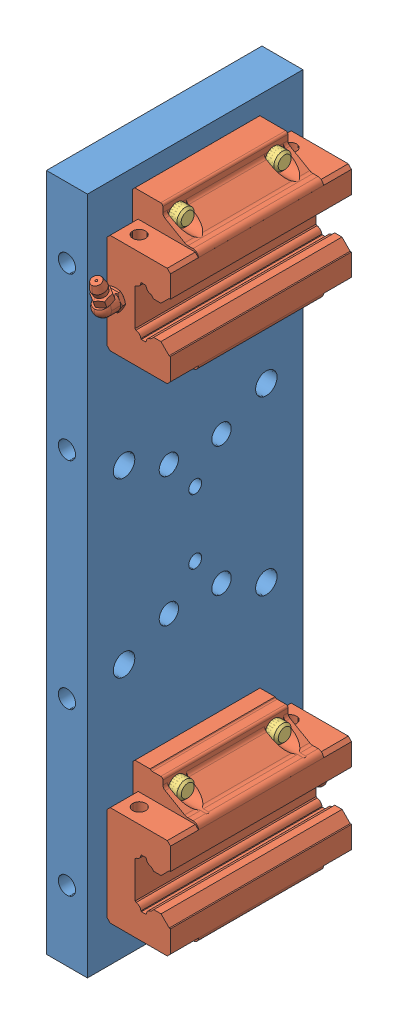
SolidWorks assembly Montagem_plataforma_patins, configuration Valor predeterminado. Lengths in mm.
Overall size (49.52 315 108.05).
11 component instances, 3 part files, 22 mates.
Components (placement in the parent):
- Plataforma-1: Plataforma [Valor predeterminado] at (-159.0513 138.7252 137.5684) x (0 1 0) z (0 0 1) size (315 19.02 100)
- KRH25-FL-N-Z0-1: KRH25-FL-N-Z0 [Valor predeterminado] at (-128.5513 253.7252 179.5684) x (0 0 -1) z (-1 0 0) size (96 70 30.5)
- KRH25-FL-N-Z0-2: KRH25-FL-N-Z0 [Valor predeterminado] at (-128.5513 23.7252 95.5184) x (0 0 1) z (-1 0 0) size (96 70 30.5)
- Allen_M8x30-1: Allen_M8x30 [ISO 4762 M8 x 30] at (-178.0713 -4.7748 160.0184) size (38 13 13)
- Allen_M8x30-2: Allen_M8x30 [ISO 4762 M8 x 30] at (-178.0713 52.2252 160.0184) size (38 13 13)
- Allen_M8x30-3: Allen_M8x30 [ISO 4762 M8 x 30] at (-178.0713 52.2252 115.0184) size (38 13 13)
- Allen_M8x30-4: Allen_M8x30 [ISO 4762 M8 x 30] at (-178.0713 -4.7748 115.0184) size (38 13 13)
- Allen_M8x30-5: Allen_M8x30 [ISO 4762 M8 x 30] at (-178.0713 225.2252 160.0684) size (38 13 13)
- Allen_M8x30-6: Allen_M8x30 [ISO 4762 M8 x 30] at (-178.0713 225.2252 115.0684) size (38 13 13)
- Allen_M8x30-7: Allen_M8x30 [ISO 4762 M8 x 30] at (-178.0713 282.2252 115.0684) size (38 13 13)
- Allen_M8x30-8: Allen_M8x30 [ISO 4762 M8 x 30] at (-178.0713 282.2252 160.0684) size (38 13 13)
Mates (geometry in assembly coordinates):
- Coincidente1: coincident anti-aligned: plane of Plataforma-1 through (-159.0513 138.7252 137.5684) normal (1 0 0); plane of KRH25-FL-N-Z0-1 through (-159.0513 260.7379 166.5684) normal (-1 0 0)
- Concêntrico3: concentric anti-aligned: cylinder of Plataforma-1 through (-178.0713 282.2252 160.0684) axis (-1 0 0) radius 7.5; cylinder of KRH25-FL-N-Z0-1 through (-151.7131 282.2252 160.0684) axis (1 0 0) radius 3.3235
- Concêntrico4: concentric anti-aligned: cylinder of Plataforma-1 through (-178.0713 225.2252 115.0684) axis (-1 0 0) radius 7.5; cylinder of KRH25-FL-N-Z0-1 through (-151.7131 225.2252 115.0684) axis (1 0 0) radius 3.3235
- Coincidente2: coincident anti-aligned: plane of Plataforma-1 through (-159.0513 138.7252 137.5684) normal (1 0 0); plane of KRH25-FL-N-Z0-2 through (-159.0513 16.7126 108.5184) normal (-1 0 0)
- Concêntrico5: concentric anti-aligned: cylinder of Plataforma-1 through (-178.0713 52.2252 115.0184) axis (-1 0 0) radius 7.5; cylinder of KRH25-FL-N-Z0-2 through (-151.7131 52.2252 115.0184) axis (1 0 0) radius 3.3235
- Concêntrico6: concentric anti-aligned: cylinder of Plataforma-1 through (-178.0713 -4.7748 160.0184) axis (-1 0 0) radius 7.5; circle of KRH25-FL-N-Z0-2
- Concêntrico71: concentric aligned: cylinder of Plataforma-1 through (-178.0713 -4.7748 160.0184) axis (-1 0 0) radius 7.5; cylinder of Allen_M8x30-1 through (-209.8213 -4.7748 160.0184) axis (-1 0 0) radius 6.5
- Concêntrico81: concentric aligned: cylinder of Plataforma-1 through (-178.0713 52.2252 160.0184) axis (-1 0 0) radius 7.5; cylinder of Allen_M8x30-2 through (-209.8213 52.2252 160.0184) axis (-1 0 0) radius 6.5
- Concêntrico91: concentric aligned: cylinder of Plataforma-1 through (-178.0713 52.2252 115.0184) axis (-1 0 0) radius 7.5; cylinder of Allen_M8x30-3 through (-209.8213 52.2252 115.0184) axis (-1 0 0) radius 6.5
- Concêntrico101: concentric aligned: cylinder of Plataforma-1 through (-178.0713 -4.7748 115.0184) axis (-1 0 0) radius 7.5; cylinder of Allen_M8x30-4 through (-209.8213 -4.7748 115.0184) axis (-1 0 0) radius 6.5
- Concêntrico111: concentric aligned: cylinder of Plataforma-1 through (-178.0713 225.2252 160.0684) axis (-1 0 0) radius 7.5; cylinder of Allen_M8x30-5 through (-217.8213 225.2252 160.0684) axis (-1 0 0) radius 6.5
- Concêntrico121: concentric aligned: cylinder of Plataforma-1 through (-178.0713 225.2252 115.0684) axis (-1 0 0) radius 7.5; cylinder of Allen_M8x30-6 through (-209.8213 225.2252 115.0684) axis (-1 0 0) radius 6.5
- Concêntrico131: concentric aligned: cylinder of Plataforma-1 through (-178.0713 282.2252 115.0684) axis (-1 0 0) radius 7.5; cylinder of Allen_M8x30-7 through (-209.8213 282.2252 115.0684) axis (-1 0 0) radius 6.5
- Concêntrico141: concentric aligned: cylinder of Plataforma-1 through (-178.0713 282.2252 160.0684) axis (-1 0 0) radius 7.5; cylinder of Allen_M8x30-8 through (-209.8213 282.2252 160.0684) axis (-1 0 0) radius 6.5
- Coincidente13: coincident: plane of Plataforma-1 through (-178.0713 138.7252 137.5684) normal (-1 0 0); point of Allen_M8x30-2
- Coincidente14: coincident aligned: plane of Plataforma-1 through (-178.0713 138.7252 137.5684) normal (-1 0 0); plane of Allen_M8x30-3 through (-178.0713 52.2252 115.0184) normal (-1 0 0)
- Coincidente15: coincident aligned: plane of Plataforma-1 through (-178.0713 138.7252 137.5684) normal (-1 0 0); plane of Allen_M8x30-4 through (-178.0713 -4.7748 115.0184) normal (-1 0 0)
- Coincidente17: coincident aligned: plane of Plataforma-1 through (-178.0713 138.7252 137.5684) normal (-1 0 0); plane of Allen_M8x30-1 through (-178.0713 -4.7748 160.0184) normal (-1 0 0)
- Coincidente18: coincident aligned: plane of Plataforma-1 through (-178.0713 138.7252 137.5684) normal (-1 0 0); plane of Allen_M8x30-8 through (-178.0713 282.2252 160.0684) normal (-1 0 0)
- Coincidente19: coincident aligned: plane of Plataforma-1 through (-178.0713 138.7252 137.5684) normal (-1 0 0); plane of Allen_M8x30-7 through (-178.0713 282.2252 115.0684) normal (-1 0 0)
- Coincidente20: coincident aligned: plane of Plataforma-1 through (-178.0713 138.7252 137.5684) normal (-1 0 0); plane of Allen_M8x30-6 through (-178.0713 225.2252 115.0684) normal (-1 0 0)
- Coincidente21: coincident aligned: plane of Plataforma-1 through (-178.0713 138.7252 137.5684) normal (-1 0 0); plane of Allen_M8x30-5 through (-178.0713 225.2252 160.0684) normal (-1 0 0)
